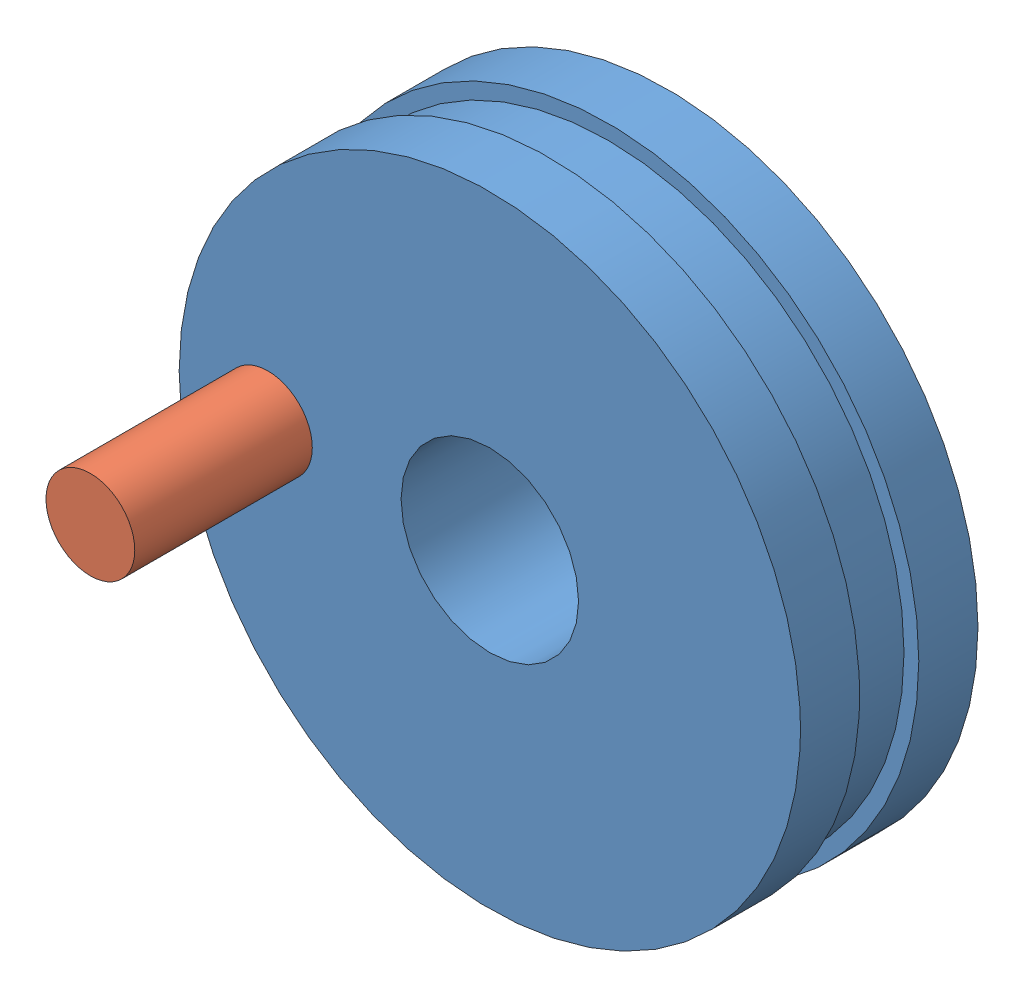
SolidWorks assembly Ensambles, configuration Predeterminado. Lengths in mm.
Overall size (147 147 84).
2 component instances, 2 part files, 2 mates.
Components (placement in the parent):
- Pieza6-1: Pieza6 [Predeterminado] at (9.8538 6.4391 7) size (147 147 42)
- Pieza7-1: Pieza7 [Predeterminado] at (-42.6462 6.4391 -21) size (21 21 84)
Mates (geometry in assembly coordinates):
- Concéntrica1: concentric: cylinder of assembly; line of assembly; cylinder of Pieza6-1 through (-42.6462 6.4391 63) axis (0 0 -1) radius 10.5; axis of Pieza7-1 through (-42.6462 6.4391 63) axis (0 0 -1)
- Coincidente1: coincident aligned: plane of Pieza6-1 through (9.8538 6.4391 -21) normal (0 0 -1); plane of Pieza7-1 through (-42.6462 6.4391 -21) normal (0 0 -1)
